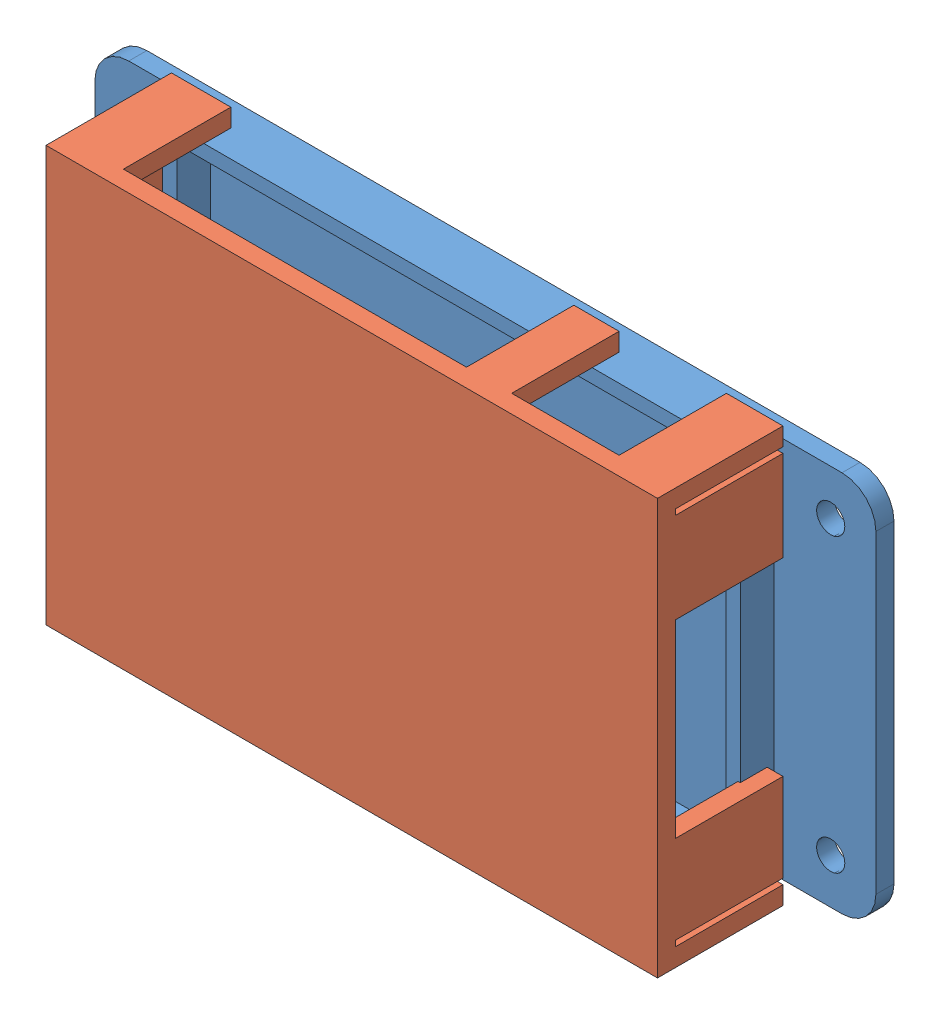
SolidWorks assembly SyncSix DC Assem, configuration Default. Lengths in mm.
Overall size (138.2 73.5 26.65).
2 component instances, 2 part files, 2 mates.
Components (placement in the parent):
- Base-1: Base [Default] at origin size (138.2 67.6 9.2)
- Cover-1: Cover [Default] at (105 -2.7 23.445) x (-1 0 0) z (0 0 -1) size (108.2 73.5 22.2)
Mates (geometry in assembly coordinates):
- Coincident1: coincident anti-aligned: plane of Base-1 through (0 0 6) normal (-1 0 0); plane of Cover-1 through (0 0.5 1.245) normal (1 0 0)
- Coincident2: coincident anti-aligned: plane of Base-1 through (0 67.6 6) normal (0 1 0); plane of Cover-1 through (101.8 67.6 1.245) normal (0 -1 0)
